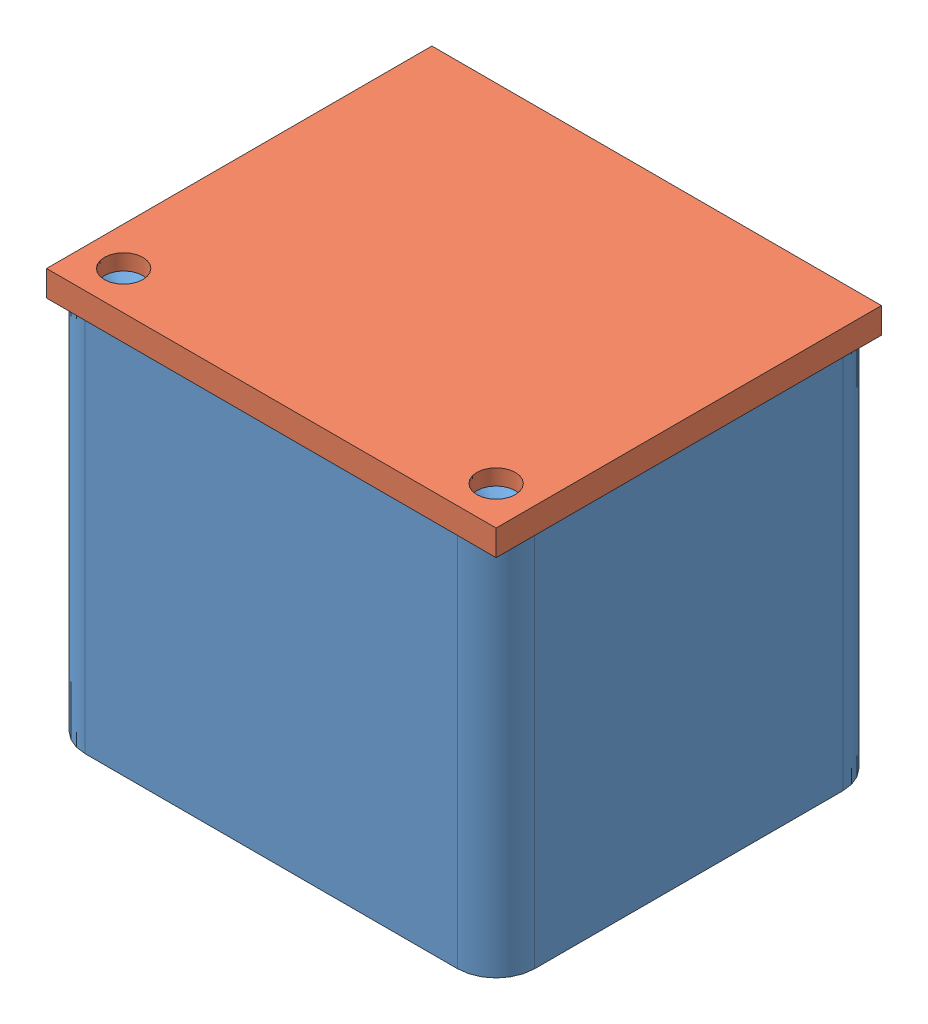
SolidWorks assembly Assem1, configuration Default. Lengths in mm.
Overall size (35 31.22 30).
2 component instances, 2 part files, 1 mates.
Components (placement in the parent):
- imubox-1: imubox [Default] at (13.8988 4.2832 35.9243) size (35 30 30)
- imu2-1: imu2 [Default] at (9.5985 35.5016 42.8611) x (1 0 0) z (0 -1 0) size (35 30 2)
Mates (geometry in assembly coordinates):
- Concentric1: concentric anti-aligned: circle of imubox-1; circle of imu2-1
